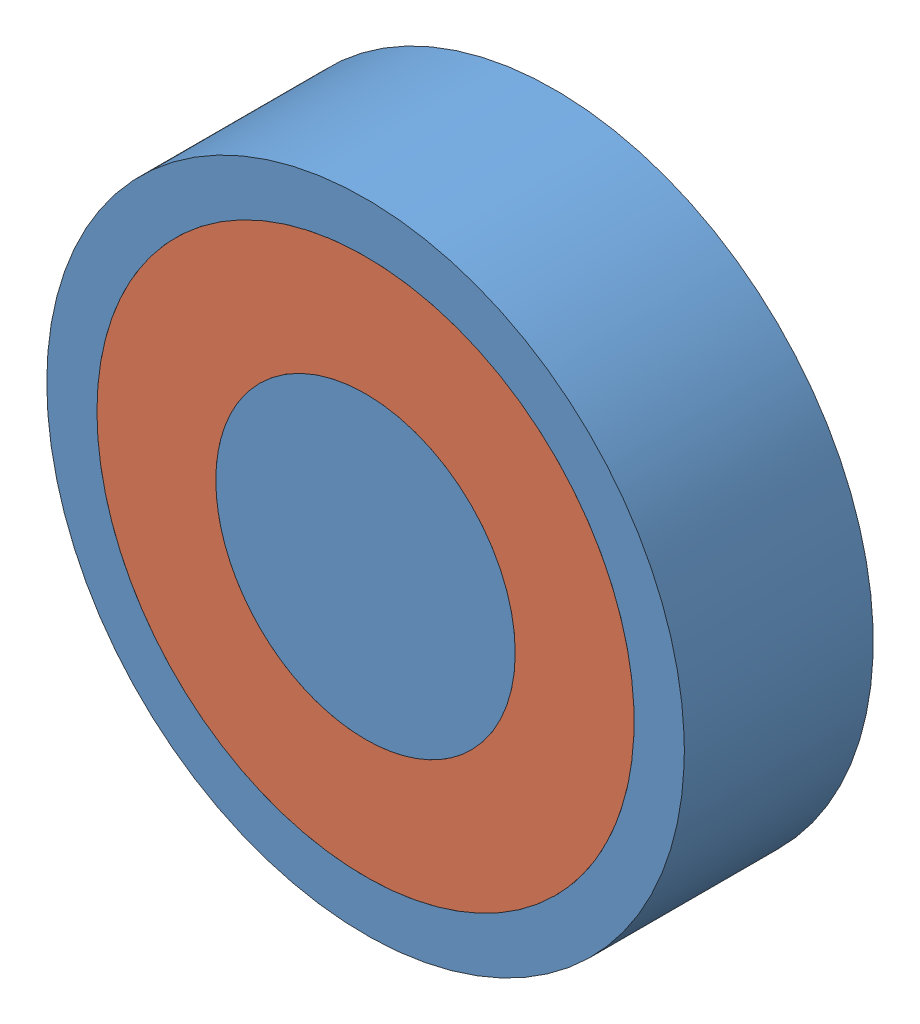
SolidWorks assembly Assem2, configuration Default. Lengths in mm.
Overall size (171.45 171.45 50.8).
2 component instances, 2 part files, 6 mates.
Components (placement in the parent):
- 19031089A_body_cfd_test-1: 19031089A_body_cfd_test [Default] at origin size (171.45 171.45 50.8)
- 19031089A_fan_cfd_test-1: 19031089A_fan_cfd_test [Default] at origin size (144.46 144.46 50.8)
Mates (geometry in assembly coordinates):
- Coincident1: coincident aligned: plane of 19031089A_body_cfd_test-1 through (94.015 0 0) normal (0 0 1)
- Coincident2: coincident aligned: plane of 19031089A_body_cfd_test-1 through (94.015 0 0) normal (0 1 0)
- Coincident3: coincident aligned: plane of 19031089A_body_cfd_test-1 through (0 0 0) normal (1 0 0)
- Coincident4: coincident aligned: plane of 19031089A_fan_cfd_test-1 through (-8.4418 0 0) normal (0 0 1)
- Coincident5: coincident aligned: plane of 19031089A_fan_cfd_test-1 through (-8.4418 0 0) normal (0 1 0)
- Coincident6: coincident aligned: plane of 19031089A_fan_cfd_test-1 through (0 0 0) normal (1 0 0)
